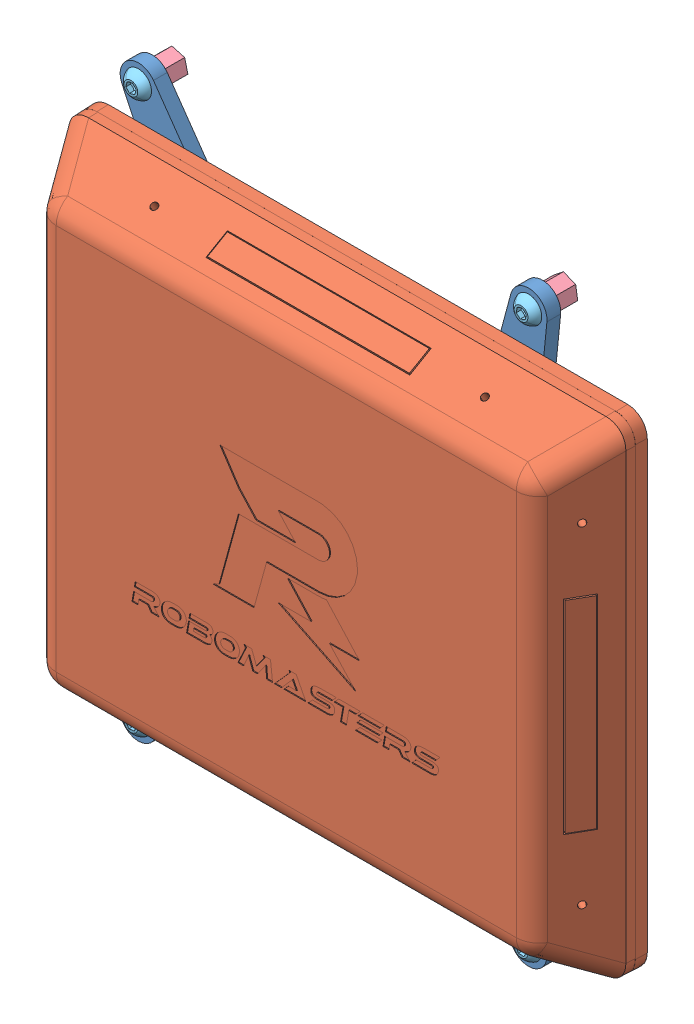
SolidWorks assembly Qxl-场地交互模块, configuration 默认. Lengths in mm.
Overall size (121.96 128.03 26.8).
14 component instances, 5 part files, 27 mates.
Components (placement in the parent):
- Qxl-场地交互安装板-1: Qxl-场地交互安装板 [默认] at (-22.8523 -6.3485 117.8649) size (93 128 3)
- RoboMaster 场地交互模块 FI02 2020 -1: RoboMaster 场地交互模块 FI02 2020  [默认] at (-22.8523 -6.3485 138.6649) x (1 0 0) z (0 1 0) size (121.96 18.8 105.96)
- 平圆头螺钉M3×8-1: 平圆头螺钉M3×8 [默认] at (8.1477 18.6515 125.8649) x (0 0 1) z (-0.923728 -0.383049 0) size (9.8 5.7 5.7)
- 平圆头螺钉M3×8-2: 平圆头螺钉M3×8 [默认] at (-53.8523 18.6515 125.8649) x (0 0 1) z (-0.85131 -0.524663 0) size (9.8 5.7 5.7)
- 平圆头螺钉M3×8-4: 平圆头螺钉M3×8 [默认] at (-53.8523 -31.3485 125.8649) x (0 0 1) z (-0.777574 -0.628792 0) size (9.8 5.7 5.7)
- 平圆头螺钉M3×8-6: 平圆头螺钉M3×8 [默认] at (8.1477 -31.3485 125.8649) x (0 0 1) z (-0.715577 -0.698533 0) size (9.8 5.7 5.7)
- M3x5不锈钢柱-1: M3x5不锈钢柱 [默认] at (-72.8523 -66.3485 117.8649) x (0.923728 0.383049 0) z (0 0 -1) size (5.77 5 5)
- M3x5不锈钢柱-2: M3x5不锈钢柱 [默认] at (12.1477 -66.3485 117.8649) x (0.85131 0.524663 0) z (0 0 -1) size (5.77 5 5)
- M3x5不锈钢柱-4: M3x5不锈钢柱 [默认] at (12.1477 53.6515 117.8649) x (0.777574 0.628792 0) z (0 0 -1) size (5.77 5 5)
- M3x5不锈钢柱-6: M3x5不锈钢柱 [默认] at (-72.8523 53.6515 117.8649) x (0.715577 0.698533 0) z (0 0 -1) size (5.77 5 5)
- 平圆头螺钉M3×6-1: 平圆头螺钉M3×6 [默认] at (12.1477 -66.3485 112.8649) x (0 0 -1) z (0.87832 0.478073 0) size (7.8 5.7 5.7)
- 平圆头螺钉M3×6-2: 平圆头螺钉M3×6 [默认] at (-72.8523 -66.3485 112.8649) x (0 0 -1) z (0.79141 0.611286 0) size (7.8 5.7 5.7)
- 平圆头螺钉M3×6-4: 平圆头螺钉M3×6 [默认] at (-72.8523 53.6515 112.8649) x (0 0 -1) z (0.707132 0.707082 0) size (7.8 5.7 5.7)
- 平圆头螺钉M3×6-6: 平圆头螺钉M3×6 [默认] at (12.1477 53.6515 112.8649) x (0 0 -1) z (0.638144 0.769917 0) size (7.8 5.7 5.7)
Mates (geometry in assembly coordinates):
- 同心1: concentric anti-aligned: cylinder of Qxl-场地交互安装板-1 through (8.1477 18.6515 120.8649) axis (0 0 -1) radius 1.65; cylinder of RoboMaster 场地交互模块 FI02 2020 -1 through (8.1477 18.6515 110.3649) axis (0 0 1) radius 1.5
- 同心2: concentric anti-aligned: cylinder of Qxl-场地交互安装板-1 through (8.1477 -31.3485 120.8649) axis (0 0 -1) radius 1.65; cylinder of RoboMaster 场地交互模块 FI02 2020 -1 through (8.1477 -31.3485 110.3649) axis (0 0 1) radius 1.5
- 重合1: coincident anti-aligned: plane of Qxl-场地交互安装板-1 through (-22.8523 -6.3485 120.8649) normal (0 0 1); plane of RoboMaster 场地交互模块 FI02 2020 -1 through (-79.4023 -54.8985 120.8649) normal (0 0 -1)
- 同心3: concentric aligned: cylinder of Qxl-场地交互安装板-1 through (8.1477 18.6515 120.8649) axis (0 0 -1) radius 1.65; cylinder of 平圆头螺钉M3×8-1 through (8.1477 18.6515 116.2149) axis (0 0 -1) radius 1.5
- 重合2: coincident anti-aligned: plane of Qxl-场地交互安装板-1 through (-22.8523 -6.3485 117.8649) normal (0 0 -1); plane of 平圆头螺钉M3×8-1 through (7.5348 20.1295 117.8649) normal (0 0 1)
- 同心4: concentric aligned: cylinder of Qxl-场地交互安装板-1 through (-53.8523 18.6515 120.8649) axis (0 0 -1) radius 1.65; cylinder of 平圆头螺钉M3×8-2 through (-53.8523 18.6515 116.2149) axis (0 0 -1) radius 1.5
- 重合3: coincident anti-aligned: plane of Qxl-场地交互安装板-1 through (-22.8523 -6.3485 117.8649) normal (0 0 -1); plane of 平圆头螺钉M3×8-2 through (-54.6917 20.0136 117.8649) normal (0 0 1)
- 同心5: concentric aligned: cylinder of Qxl-场地交互安装板-1 through (-53.8523 -31.3485 120.8649) axis (0 0 -1) radius 1.65; cylinder of 平圆头螺钉M3×8-4 through (-53.8523 -31.3485 116.2149) axis (0 0 -1) radius 1.5
- 重合4: coincident anti-aligned: plane of Qxl-场地交互安装板-1 through (-22.8523 -6.3485 117.8649) normal (0 0 -1); plane of 平圆头螺钉M3×8-4 through (-54.8584 -30.1044 117.8649) normal (0 0 1)
- 同心6: concentric aligned: cylinder of Qxl-场地交互安装板-1 through (8.1477 -31.3485 120.8649) axis (0 0 -1) radius 1.65; cylinder of 平圆头螺钉M3×8-6 through (8.1477 -31.3485 116.2149) axis (0 0 -1) radius 1.5
- 重合5: coincident anti-aligned: plane of Qxl-场地交互安装板-1 through (-22.8523 -6.3485 117.8649) normal (0 0 -1); plane of 平圆头螺钉M3×8-6 through (7.0301 -30.2036 117.8649) normal (0 0 1)
- 同心7: concentric aligned: cylinder of Qxl-场地交互安装板-1 through (-72.8523 -66.3485 117.8649) axis (0 0 1) radius 1.65; cylinder of M3x5不锈钢柱-1 through (-72.8523 -66.3485 112.8649) axis (0 0 1) radius 1.5
- 重合6: coincident anti-aligned: plane of Qxl-场地交互安装板-1 through (-22.8523 -6.3485 117.8649) normal (0 0 -1); plane of M3x5不锈钢柱-1 through (-72.8523 -66.3485 117.8649) normal (0 0 1)
- 同心8: concentric aligned: cylinder of Qxl-场地交互安装板-1 through (12.1477 -66.3485 117.8649) axis (0 0 1) radius 1.65; cylinder of M3x5不锈钢柱-2 through (12.1477 -66.3485 112.8649) axis (0 0 1) radius 1.5
- 重合7: coincident anti-aligned: plane of Qxl-场地交互安装板-1 through (-22.8523 -6.3485 117.8649) normal (0 0 -1); plane of M3x5不锈钢柱-2 through (12.1477 -66.3485 117.8649) normal (0 0 1)
- 同心9: concentric aligned: cylinder of Qxl-场地交互安装板-1 through (12.1477 53.6515 117.8649) axis (0 0 1) radius 1.65; cylinder of M3x5不锈钢柱-4 through (12.1477 53.6515 112.8649) axis (0 0 1) radius 1.5
- 重合8: coincident anti-aligned: plane of Qxl-场地交互安装板-1 through (-22.8523 -6.3485 117.8649) normal (0 0 -1); plane of M3x5不锈钢柱-4 through (12.1477 53.6515 117.8649) normal (0 0 1)
- 同心10: concentric aligned: cylinder of Qxl-场地交互安装板-1 through (-72.8523 53.6515 117.8649) axis (0 0 1) radius 1.65; cylinder of M3x5不锈钢柱-6 through (-72.8523 53.6515 112.8649) axis (0 0 1) radius 1.5
- 重合9: coincident anti-aligned: plane of Qxl-场地交互安装板-1 through (-22.8523 -6.3485 117.8649) normal (0 0 -1); plane of M3x5不锈钢柱-6 through (-72.8523 53.6515 117.8649) normal (0 0 1)
- 同心11: concentric aligned: cylinder of Qxl-场地交互安装板-1 through (12.1477 -66.3485 117.8649) axis (0 0 1) radius 1.65; cylinder of 平圆头螺钉M3×6-1 through (12.1477 -66.3485 122.5149) axis (0 0 1) radius 1.5
- 重合10: coincident anti-aligned: plane of Qxl-场地交互安装板-1 through (-22.8523 -6.3485 120.8649) normal (0 0 1); plane of 平圆头螺钉M3×6-1 through (11.3828 -64.9432 120.8649) normal (0 0 -1)
- 同心12: concentric aligned: cylinder of Qxl-场地交互安装板-1 through (-72.8523 -66.3485 117.8649) axis (0 0 1) radius 1.65; cylinder of 平圆头螺钉M3×6-2 through (-72.8523 -66.3485 122.5149) axis (0 0 1) radius 1.5
- 重合11: coincident anti-aligned: plane of Qxl-场地交互安装板-1 through (-22.8523 -6.3485 120.8649) normal (0 0 1); plane of 平圆头螺钉M3×6-2 through (-73.8303 -65.0823 120.8649) normal (0 0 -1)
- 同心13: concentric aligned: cylinder of Qxl-场地交互安装板-1 through (-72.8523 53.6515 117.8649) axis (0 0 1) radius 1.65; cylinder of 平圆头螺钉M3×6-4 through (-72.8523 53.6515 122.5149) axis (0 0 1) radius 1.5
- 重合12: coincident anti-aligned: plane of Qxl-场地交互安装板-1 through (-22.8523 -6.3485 120.8649) normal (0 0 1); plane of 平圆头螺钉M3×6-4 through (-73.9836 54.7829 120.8649) normal (0 0 -1)
- 同心14: concentric aligned: cylinder of Qxl-场地交互安装板-1 through (12.1477 53.6515 117.8649) axis (0 0 1) radius 1.65; cylinder of 平圆头螺钉M3×6-6 through (12.1477 53.6515 122.5149) axis (0 0 1) radius 1.5
- 重合13: coincident anti-aligned: plane of Qxl-场地交互安装板-1 through (-22.8523 -6.3485 120.8649) normal (0 0 1); plane of 平圆头螺钉M3×6-6 through (10.9158 54.6725 120.8649) normal (0 0 -1)
